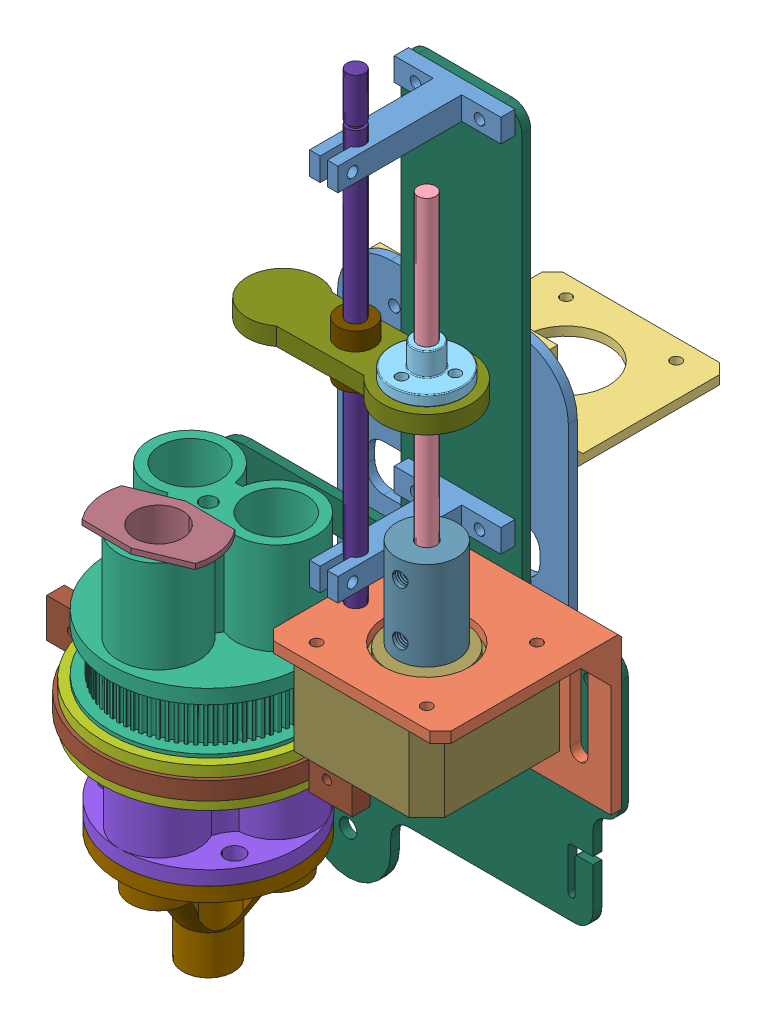
SolidWorks assembly extrusion system assembly - Ver 2, configuration Default. Lengths in mm.
Overall size (120 229.01 156.48).
21 component instances, 19 part files, 41 mates.
Components (placement in the parent):
- Aluminium plate 2-1: Aluminium plate 2 [Default] at (-24.8 0 -29.5) size (65 125.41 2.5)
- nema_17_holder-1: nema_17_holder [Default] at (39.6 57.4093 32.35) x (1 0 0) z (0 -1 0) size (50 51 43)
- NEMA 17 HOLDER 2-1: NEMA 17 HOLDER 2 [Default] at (-12.9 51.5 -59.35) x (1 0 0) z (0 1 0) size (50 51 32.5)
- lead screw-1: lead screw [Default] at (39.6 119.9093 32.35) x (0 1 0) z (0 0 1) size (95 5 5)
- trap nut-1: trap nut [Default] at (39.6 124.8108 32.35) x (-0.77693 0 -0.629587) z (0 -1 0) size (20 20 9.4)
- syringe barrel assembly-1: syringe barrel assembly [Default] at (-12.4 27.4093 41.8428) size (68.27 112.01 68.27)
  - barrel mid 1-1: barrel mid 1 [Default] at origin size (55 48.5 55)
  - aluminium ring-1: aluminium ring [Default] at (0 -5.5 0) size (60 11 60)
  - barrel bottom 1-1: barrel bottom 1 [Default] at (0 -33 0) x (0.999998 0 -0.001745) z (0.001745 0 0.999998) size (55 27.4 55)
  - mixing chamber 1-1: mixing chamber 1 [Default] at (0 -68 0) x (-0.866897 0 -0.498488) z (0 1 0) size (50 50 36.01)
- barrel lock p1-1: barrel lock p1 [Default] at (-12.4 19.4093 41.8428) x (0 0 -1) z (1 0 0) size (46.34 23.5 80)
- barrel lock p2-1: barrel lock p2 [Default] at (-12.4 24.4093 41.8428) x (0 0 -1) z (-1 0 0) size (33.5 11 86)
- Nema17 motor-1: Nema17 motor [Default] at (39.6 33.4093 32.35) size (42.3 38 42.3)
- syringe 10 ml part1-1: syringe 10 ml part1 [Default] at (-12.4 32.9093 55.8428) x (0 -1 0) z (0.190524 0 0.981683) size (86.5 30.6 19.5)
- coupler-1: coupler [Default] at (39.6 57.4093 32.35) x (0.995719 0 -0.092427) z (0.092427 0 0.995719) size (17 25 17)
- Aluminium plate 1 - Ver 2-1: Aluminium plate 1 - Ver 2 [Default] at origin size (116 210.75 2.5)
- pusher with linear rod-1: pusher with linear rod [Default] at (39.6 116.8108 32.35) size (62.5 5 25)
- linear shaft-1: linear shaft [Default] at (19.6 122.4093 32.35) x (0 -1 0) z (0.957553 0 -0.288256) size (130 5 5)
- linear bearing-1: linear bearing [Default] at (19.6 119.3108 32.35) x (0 -1 0) z (0.393325 0 0.919399) size (15 10 10)
- linear shaft holder-1: linear shaft holder [Default] at (19.6 163 4.5042) size (30 7 38.85)
- linear shaft holder-2: linear shaft holder [Default] at (19.6 63 4.5042) size (30 7 38.85)
Mates (geometry in assembly coordinates):
- Concentric5: concentric: cylinder of nema_17_holder-1 through (39.6 54.4093 32.35) axis (0 1 0) radius 12; cylinder of lead screw-1 through (39.6 110.7738 32.35) axis (0 -1 0) radius 2.5
- Distance12: distance = 15 mm: plane of lead screw-1 through (37.1 72.4093 32.35) normal (0 -1 0); plane of nema_17_holder-1 through (39.6 57.4093 32.35) normal (0 1 0)
- Concentric6: concentric: cylinder of lead screw-1 through (39.6 110.7738 32.35) axis (0 -1 0) radius 2.5; cylinder of trap nut-1 through (39.6 121.8108 32.35) axis (0 1 0) radius 2.5
- Distance13: distance = 5 mm: plane of trap nut-1 through (39.5 131.2108 32.35) normal (0 1 0); plane of lead screw-1 through (37 68.3 32.35) normal (0 -1 0)
- Coincident20: coincident: plane of Aluminium plate 2-1 through (-24.8 0 -29.5) normal (0 1 0); plane of assembly through (0 0 0) normal (0 1 0)
- Distance16: distance = 12.4 mm: plane of barrel lock p1-1 through (-12.4 19.4093 41.8428) normal (1 0 0); plane of assembly through (0 0 0) normal (1 0 0)
- Concentric9: concentric: cylinder of syringe barrel assembly-1/aluminium ring-1 through (-12.4 41.8967 41.8428) axis (0 1 0) radius 25; cylinder of barrel lock p1-1 through (-12.4 24.4093 41.8428) axis (0 -1 0) radius 25
- Coincident26: coincident: plane of barrel lock p2-1 through (-12.4 19.4093 41.8428) normal (0 -1 0); plane of syringe barrel assembly-1/aluminium ring-1 through (-37.4 19.4093 41.8428) normal (0 1 0)
- Coincident27: coincident: plane of syringe barrel assembly-1/aluminium ring-1 through (-37.4 24.4093 41.8428) normal (0 -1 0); plane of barrel lock p2-1 through (-12.4 24.4093 41.8428) normal (0 1 0)
- Concentric11: concentric: cylinder of syringe barrel assembly-1/aluminium ring-1 through (-12.4 41.8967 41.8428) axis (0 1 0) radius 25; cylinder of barrel lock p2-1 through (-12.4 19.4093 41.8428) axis (0 1 0) radius 25
- Coincident28: coincident: plane of barrel lock p1-1 through (-12.4 24.4093 41.8428) normal (0 0 1); plane of barrel lock p2-1 through (-12.4 19.4093 41.8428) normal (0 0 -1)
- Distance17: distance = 27 mm: plane of nema_17_holder-1 through (14.6 54.4093 50.5) normal (-1 0 0); plane of syringe barrel assembly-1/barrel mid 1-1 through (-12.4 27.4093 41.8428) normal (1 0 0)
- Distance19: distance = 13 mm: plane of nema_17_holder-1 through (39.6 57.4093 32.35) normal (0 1 0); plane of syringe barrel assembly-1/barrel mid 1-1 through (-12.4 44.4093 41.8428) normal (0 1 0)
- Coincident35: coincident: plane of Aluminium plate 2-1 through (-24.8 0 -29.5) normal (0 0 -1); plane of NEMA 17 HOLDER 2-1 through (12.1 54 -29.5) normal (0 0 1)
- Distance21: distance = 7 mm: plane of NEMA 17 HOLDER 2-1 through (-37.9 54 -59.35) normal (-1 0 0); plane of Aluminium plate 2-1 through (-44.9 0 -29.501) normal (-1 0 0)
- Distance22: distance = 10.5 mm: plane of Aluminium plate 2-1 through (-24.8 41 -29.501) normal (0 -1 0); plane of NEMA 17 HOLDER 2-1 through (-12.9 51.5 -59.35) normal (0 -1 0)
- Parallel1: parallel: plane of syringe barrel assembly-1/barrel mid 1-1 through (-12.4 27.4093 41.8428) normal (1 0 0); plane of assembly through (0 0 0) normal (1 0 0)
- Concentric12: concentric: cylinder of nema_17_holder-1 through (39.6 54.4093 32.35) axis (0 1 0) radius 12; cylinder of Nema17 motor-1 through (39.6 56.4093 32.35) axis (0 -1 0) radius 11
- Concentric13: concentric: cylinder of Nema17 motor-1 through (55.1 51.4093 16.85) axis (0 1 0) radius 1.5; cylinder of nema_17_holder-1 through (55.1 54.4093 16.85) axis (0 1 0) radius 1.5
- Coincident36: coincident: plane of nema_17_holder-1 through (39.6 54.4093 32.35) normal (0 -1 0); plane of Nema17 motor-1 through (39.6 54.4093 32.35) normal (0 1 0)
- Concentric14: concentric: cylinder of syringe barrel assembly-1/barrel mid 1-1 through (-12.4 70.4093 55.8428) axis (0 -1 0) radius 8.425; cylinder of syringe 10 ml part1-1 through (-12.4 83.0267 55.8428) axis (0 1 0) radius 8.25
- Coincident38: coincident: plane of syringe barrel assembly-1/barrel mid 1-1 through (-12.4 70.4093 41.8428) normal (0 1 0); plane of syringe 10 ml part1-1 through (-4.3011 70.4093 54.271) normal (0 -1 0)
- Concentric15: concentric: cylinder of Nema17 motor-1 through (39.6 71.4093 32.35) axis (0 -1 0) radius 2.5; cylinder of coupler-1 through (39.6 57.4093 32.35) axis (0 1 0) radius 2.7
- Distance24: distance = 27 mm: plane of Aluminium plate 2-1 through (-24.8 0 -27) normal (0 0 1); plane of Aluminium plate 1 - Ver 2-1 through (0 0 0) normal (0 0 -1)
- Coincident40: coincident: plane of nema_17_holder-1 through (64.6 54.4093 2.5) normal (0 0 -1); plane of Aluminium plate 1 - Ver 2-1 through (0 0 2.5) normal (0 0 1)
- Parallel3: parallel: plane of barrel lock p1-1 through (-24.9 24.4093 -4.5) normal (-1 0 0); plane of Aluminium plate 1 - Ver 2-1 through (-22.4 24.4093 -0.001) normal (1 0 0)
- Coincident43: coincident: plane of barrel lock p1-1 through (-12.4 24.4093 2.5) normal (0 0 -1); plane of Aluminium plate 1 - Ver 2-1 through (0 0 2.5) normal (0 0 1)
- Coincident44: coincident: plane of barrel lock p1-1 through (0.1 24.4093 -4.5) normal (0 1 0); plane of Aluminium plate 1 - Ver 2-1 through (-22.4 24.4093 -0.001) normal (0 -1 0)
- Concentric16: concentric: cylinder of lead screw-1 through (39.6 110.7738 32.35) axis (0 -1 0) radius 2.5; cylinder of pusher with linear rod-1 through (39.6 121.8108 32.35) axis (0 -1 0) radius 3
- Coincident45: coincident: plane of trap nut-1 through (39.6 121.8108 32.35) normal (0 -1 0); plane of pusher with linear rod-1 through (39.6 121.8108 32.35) normal (0 1 0)
- Parallel4: parallel: plane of pusher with linear rod-1 through (39.6 116.8108 32.35) normal (0 0 1); plane of assembly through (0 0 0) normal (0 0 1)
- Concentric17: concentric: cylinder of pusher with linear rod-1 through (19.6 121.8108 32.35) axis (0 -1 0) radius 5.1; cylinder of linear shaft-1 through (19.6 172.058 32.35) axis (0 1 0) radius 2.5
- Coincident47: coincident: plane of nema_17_holder-1 through (39.6 57.4093 32.35) normal (0 1 0); plane of linear shaft-1 through (18.8794 57.4093 29.9561) normal (0 -1 0)
- Concentric18: concentric: cylinder of pusher with linear rod-1 through (19.6 121.8108 32.35) axis (0 -1 0) radius 5.1; cylinder of linear bearing-1 through (19.6 185.2235 32.35) axis (0 1 0) radius 5
- Distance25: distance = 2.5 mm: plane of linear bearing-1 through (19.6 119.3108 32.35) normal (0 -1 0); plane of pusher with linear rod-1 through (39.6 116.8108 32.35) normal (0 1 0)
- Concentric19: concentric: cylinder of linear shaft-1 through (19.6 172.058 32.35) axis (0 1 0) radius 2.5; cylinder of linear shaft holder-2 through (19.6 70 32.35) axis (0 -1 0) radius 2.6
- Concentric20: concentric: cylinder of linear shaft-1 through (19.6 172.058 32.35) axis (0 1 0) radius 2.5; cylinder of linear shaft holder-1 through (19.6 170 32.35) axis (0 -1 0) radius 2.6
- Coincident50: coincident: plane of Aluminium plate 1 - Ver 2-1 through (0 170 2.5) normal (0 1 0); plane of linear shaft holder-1 through (19.6 170 4.5042) normal (0 1 0)
- Distance26: distance = 1 mm: plane of coupler-1 through (39.6 57.4093 32.35) normal (0 -1 0); plane of Nema17 motor-1 through (39.6 56.4093 32.35) normal (0 1 0)
- Coincident51: coincident: plane of barrel lock p1-1 through (-12.4 19.4093 41.8428) normal (0 -1 0); plane of barrel lock p2-1 through (-52.4 19.4093 39.3428) normal (0 1 0)
- Parallel5: parallel: cylinder of Aluminium plate 1 - Ver 2-1 through (10.5 66.5 -7.5) axis (0 0 1) radius 1.5; cylinder of linear shaft holder-2 through (10.6 66.5 1.5084) axis (0 0 1) radius 1.5
